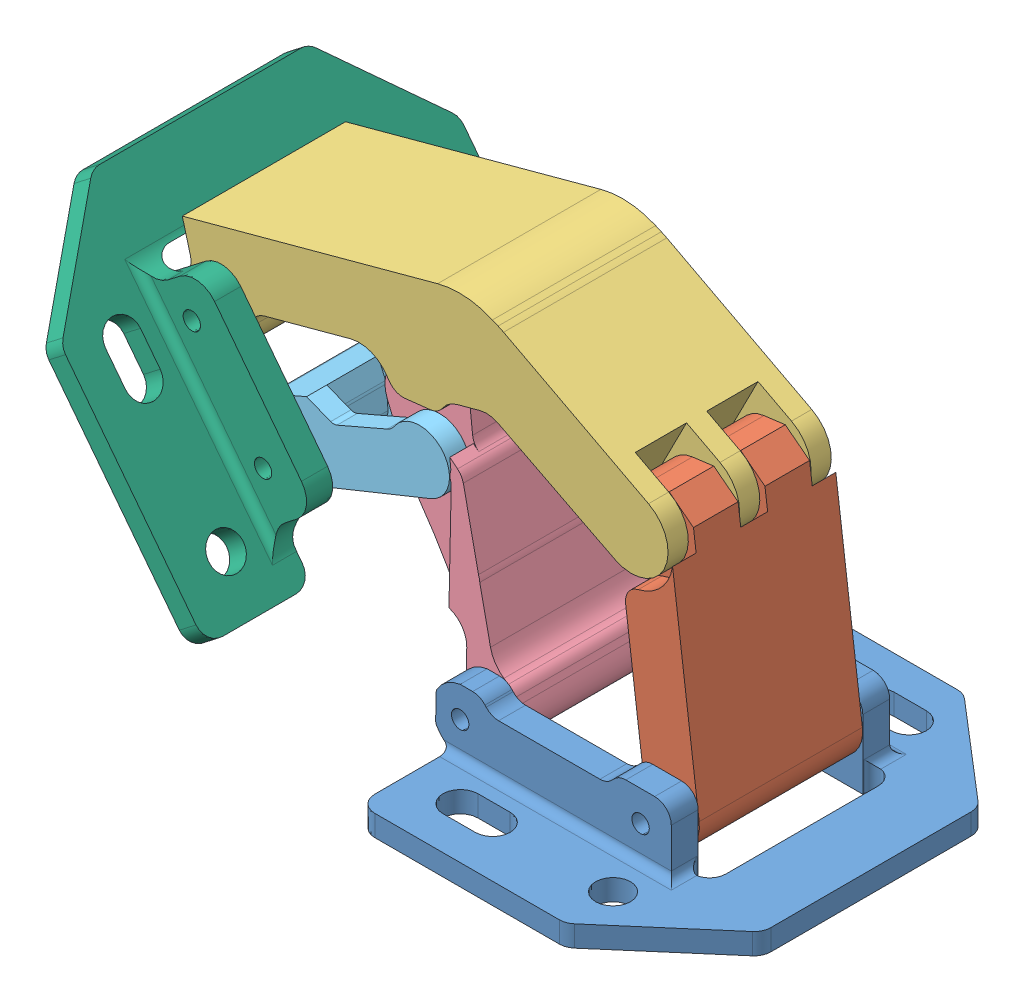
SolidWorks assembly SurfaceHinge, configuration Default. Lengths in mm.
Overall size (83.24 52.07 48.39).
6 component instances, 6 part files, 13 mates.
Components (placement in the parent):
- Base_Door_Side_AK-1: Base_Door_Side_AK [Default] at (73.1135 0 -41.3059) x (1 0 -0.00051) z (0.00051 0 1) size (39.28 10.32 48)
- Part3-1: Part3 [Default] at (64.6316 11.1133 -55.3766) x (-0.4565 0.889723 0.000233) z (-0.00051 0 -1) size (33.08 16.89 19.68)
- Part1-1: Part1 [Default] at (93.8379 -1.6494 -74.2515) x (-0.989991 0.141127 0.000505) z (-0.00051 0 -1) size (58.81 23.96 19.68)
- Part5-1: Part5 [Default] at (69.2498 5.1623 -72.3889) x (0.51467 -0.857389 -0.000262) z (0.00051 0 1) size (37.69 15.27 19.68)
- Part4-1: Part4 [Default] at (96.7322 3.6545 -74.4229) x (-0.980766 -0.195187 0.0005) z (-0.00051 0 -1) size (23.73 10.4 19.68)
- Base_Frame_Side_AK-1: Base_Frame_Side_AK [Default] at (52.3679 7.9046 -89.6953) x (-0.61115 0.791514 0.000312) z (-0.00051 0 -1) size (40.4 10.32 48)
Mates (geometry in assembly coordinates):
- Concentric2: concentric aligned: cylinder of Base_Door_Side_AK-1 through (74.559 6.64 -89.3066) axis (0.00051 0 1) radius 1.05; cylinder of Part5-1 through (74.5641 6.64 -79.3753) axis (0.00051 0 1) radius 1.05
- Concentric3: concentric aligned: cylinder of Base_Door_Side_AK-1 through (96.289 6.64 -89.3177) axis (0.00051 0 1) radius 1.05; cylinder of Part3-1 through (96.2963 6.64 -75.0727) axis (0.00051 0 1) radius 1.05
- Concentric4: concentric anti-aligned: cylinder of Part5-1 through (65.8498 27.4734 -75.2272) axis (0.00051 0 1) radius 2.25; cylinder of Part4-1 through (65.8625 27.4734 -50.2903) axis (-0.00051 0 -1) radius 2
- Concentric5: concentric anti-aligned: cylinder of Part1-1 through (65.4683 36.3613 -50.1201) axis (-0.00051 0 -1) radius 2; cylinder of Part5-1 through (65.4555 36.3613 -75.227) axis (0.00051 0 1) radius 2.25
- Concentric6: concentric aligned: cylinder of Part3-1 through (91.5702 32.9585 -55.3903) axis (-0.00051 0 -1) radius 2.25; cylinder of Part1-1 through (91.5728 32.9585 -50.1334) axis (-0.00051 0 -1) radius 2
- Coincident1: coincident anti-aligned: plane of Base_Door_Side_AK-1 through (73.0962 -29.2903 -75.2309) normal (0.00051 0 1); plane of Part5-1 through (68.8096 11.247 -75.2287) normal (-0.00051 0 -1)
- Coincident2: coincident anti-aligned: plane of Base_Door_Side_AK-1 through (73.1063 -29.2903 -55.3809) normal (-0.00051 0 -1); plane of Part3-1 through (91.5702 32.9585 -55.3903) normal (0.00051 0 1)
- Coincident3: coincident anti-aligned: plane of Part3-1 through (91.5687 32.9585 -58.2303) normal (0.00051 0 1); plane of Part1-1 through (91.5687 32.9585 -58.2303) normal (-0.00051 0 -1)
- Coincident4: coincident anti-aligned: plane of Part5-1 through (69.6481 5.326 -58.3891) normal (0.00051 0 1); plane of Part4-1 through (65.8584 27.4734 -58.3872) normal (-0.00051 0 -1)
- Concentric7: concentric aligned: cylinder of Part1-1 through (41.7511 31.614 -73.0049) axis (-0.00051 0 -1) radius 1.05; cylinder of Base_Frame_Side_AK-1 through (41.7671 31.614 -41.6899) axis (-0.00051 0 -1) radius 1.05
- Concentric8: concentric aligned: cylinder of Part4-1 through (50.3316 20.5012 -73.1793) axis (-0.00051 0 -1) radius 1.05; cylinder of Base_Frame_Side_AK-1 through (50.3476 20.5012 -41.6943) axis (-0.00051 0 -1) radius 1.05
- Coincident5: coincident anti-aligned: plane of Part1-1 through (37.4595 38.8174 -55.7627) normal (0.00051 0 1); plane of Base_Frame_Side_AK-1 through (33.9241 -6.3497 -55.7609) normal (-0.00051 0 -1)
- Coincident6: coincident anti-aligned: plane of Base_Door_Side_AK-1 through (73.1135 0 -41.3059) normal (0 -1 0)
